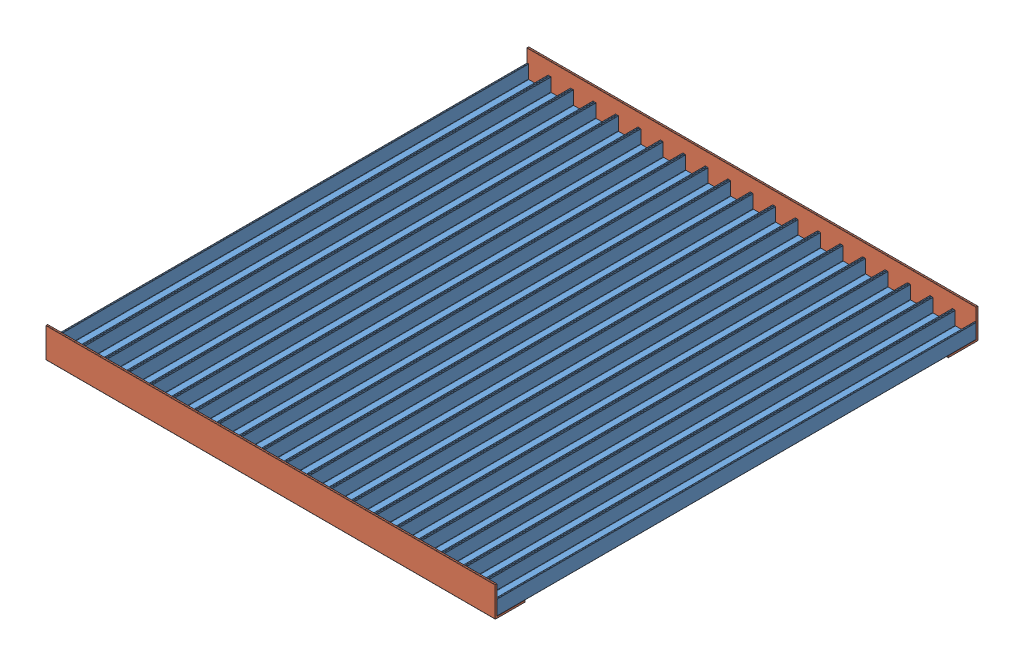
SolidWorks assembly Сборка1, configuration По умолчанию. Lengths in mm.
Overall size (300 20 322.4).
22 component instances, 2 part files, 97 mates.
Components (placement in the parent):
- hot_bed_profile-1: hot_bed_profile [По умолчанию] at (155.3452 184.886 41.526) size (15 10 320)
- hot_bed_profile-2: hot_bed_profile [По умолчанию] at (140.3452 184.886 41.526) size (15 10 320)
- hot_bed_profile-3: hot_bed_profile [По умолчанию] at (185.3452 184.886 41.526) size (15 10 320)
- hot_bed_profile-4: hot_bed_profile [По умолчанию] at (170.3452 184.886 41.526) size (15 10 320)
- hot_bed_profile-7: hot_bed_profile [По умолчанию] at (230.3452 184.886 41.526) size (15 10 320)
- hot_bed_profile-8: hot_bed_profile [По умолчанию] at (215.3452 184.886 41.526) size (15 10 320)
- hot_bed_profile-9: hot_bed_profile [По умолчанию] at (200.3452 184.886 41.526) size (15 10 320)
- hot_bed_profile-10: hot_bed_profile [По умолчанию] at (245.3452 184.886 41.526) size (15 10 320)
- hot_bed_profile-11: hot_bed_profile [По умолчанию] at (365.3452 184.886 41.526) size (15 10 320)
- hot_bed_profile-12: hot_bed_profile [По умолчанию] at (320.3452 184.886 41.526) size (15 10 320)
- hot_bed_profile-13: hot_bed_profile [По умолчанию] at (335.3452 184.886 41.526) size (15 10 320)
- hot_bed_profile-14: hot_bed_profile [По умолчанию] at (350.3452 184.886 41.526) size (15 10 320)
- hot_bed_profile-15: hot_bed_profile [По умолчанию] at (290.3452 184.886 41.526) size (15 10 320)
- hot_bed_profile-16: hot_bed_profile [По умолчанию] at (275.3452 184.886 41.526) size (15 10 320)
- hot_bed_profile-17: hot_bed_profile [По умолчанию] at (260.3452 184.886 41.526) size (15 10 320)
- hot_bed_profile-18: hot_bed_profile [По умолчанию] at (305.3452 184.886 41.526) size (15 10 320)
- hot_bed_profile-19: hot_bed_profile [По умолчанию] at (395.3452 184.886 41.526) size (15 10 320)
- hot_bed_profile-20: hot_bed_profile [По умолчанию] at (380.3452 184.886 41.526) size (15 10 320)
- hot_bed_profile-26: hot_bed_profile [По умолчанию] at (410.3452 184.886 41.526) size (15 10 320)
- hot_bed_profile-27: hot_bed_profile [По умолчанию] at (425.3452 184.886 41.526) size (15 10 320)
- hot_bed_profile_corner-1: hot_bed_profile_corner [По умолчанию] at (440.3452 194.6038 362.726) x (0 1 0) z (0 0 1) size (20 300 20)
- hot_bed_profile_corner-3: hot_bed_profile_corner [По умолчанию] at (440.3452 183.686 51.2438) x (0 0 1) z (0 -1 0) size (20 300 20)
Mates (geometry in assembly coordinates):
- Совпадение2: coincident anti-aligned: line of hot_bed_profile-1 through (155.3452 185.086 361.526) axis (0 1 0); line of hot_bed_profile-2 through (155.3452 194.686 361.526) axis (0 -1 0)
- Совпадение3: coincident anti-aligned: plane of hot_bed_profile-1 through (155.3452 185.086 361.526) normal (-1 0 0); plane of hot_bed_profile-2 through (155.3452 194.686 361.526) normal (1 0 0)
- Совпадение4: coincident anti-aligned: plane of hot_bed_profile-3 through (185.3452 185.086 361.526) normal (-1 0 0); plane of hot_bed_profile-4 through (185.3452 194.686 361.526) normal (1 0 0)
- Совпадение5: coincident anti-aligned: line of hot_bed_profile-3 through (185.3452 185.086 361.526) axis (0 1 0); line of hot_bed_profile-4 through (185.3452 194.686 361.526) axis (0 -1 0)
- Совпадение7: coincident aligned: plane of hot_bed_profile-1 through (156.1452 194.686 361.526) normal (0 0 1); plane of hot_bed_profile-4 through (171.1452 194.686 361.526) normal (0 0 1)
- Совпадение10: coincident aligned: plane of hot_bed_profile-3 through (186.1452 194.686 361.526) normal (0 0 1); plane of hot_bed_profile-4 through (171.1452 194.686 361.526) normal (0 0 1)
- Совпадение13: coincident anti-aligned: plane of hot_bed_profile-1 through (170.3452 194.686 361.526) normal (1 0 0); plane of hot_bed_profile-4 through (170.3452 185.086 361.526) normal (-1 0 0)
- Совпадение14: coincident anti-aligned: plane of hot_bed_profile-1 through (170.3452 194.686 361.526) normal (1 0 0); plane of hot_bed_profile-4 through (170.3452 185.086 361.526) normal (-1 0 0)
- Совпадение15: coincident anti-aligned: plane of hot_bed_profile-1 through (155.3452 185.086 361.526) normal (-1 0 0); plane of hot_bed_profile-2 through (155.3452 194.686 361.526) normal (1 0 0)
- Совпадение18: coincident anti-aligned: plane of hot_bed_profile-8 through (215.3452 185.086 361.526) normal (-1 0 0); plane of hot_bed_profile-9 through (215.3452 194.686 361.526) normal (1 0 0)
- Совпадение19: coincident aligned: plane of hot_bed_profile-7 through (231.1452 194.686 361.526) normal (0 0 1); plane of hot_bed_profile-10 through (246.1452 194.686 361.526) normal (0 0 1)
- Совпадение20: coincident anti-aligned: line of hot_bed_profile-7 through (245.3452 194.686 361.526) axis (0 -1 0); line of hot_bed_profile-10 through (245.3452 185.086 361.526) axis (0 1 0)
- Совпадение21: coincident anti-aligned: plane of hot_bed_profile-8 through (215.3452 185.086 361.526) normal (-1 0 0); plane of hot_bed_profile-9 through (215.3452 194.686 361.526) normal (1 0 0)
- Совпадение22: coincident anti-aligned: plane of hot_bed_profile-7 through (245.3452 194.686 361.526) normal (1 0 0); plane of hot_bed_profile-10 through (245.3452 185.086 361.526) normal (-1 0 0)
- Совпадение23: coincident anti-aligned: plane of hot_bed_profile-7 through (230.3452 185.086 361.526) normal (-1 0 0); plane of hot_bed_profile-8 through (230.3452 194.686 361.526) normal (1 0 0)
- Совпадение24: coincident aligned: plane of hot_bed_profile-7 through (231.1452 194.686 361.526) normal (0 0 1); plane of hot_bed_profile-8 through (216.1452 194.686 361.526) normal (0 0 1)
- Совпадение25: coincident anti-aligned: line of hot_bed_profile-8 through (215.3452 185.086 361.526) axis (0 1 0); line of hot_bed_profile-9 through (215.3452 194.686 361.526) axis (0 -1 0)
- Совпадение26: coincident anti-aligned: plane of hot_bed_profile-7 through (230.3452 185.086 361.526) normal (-1 0 0); plane of hot_bed_profile-8 through (230.3452 194.686 361.526) normal (1 0 0)
- Совпадение28: coincident anti-aligned: plane of hot_bed_profile-3 through (200.3452 194.686 361.526) normal (1 0 0); plane of hot_bed_profile-9 through (200.3452 185.086 361.526) normal (-1 0 0)
- Совпадение29: coincident anti-aligned: plane of hot_bed_profile-3 through (200.3452 194.686 361.526) normal (1 0 0); plane of hot_bed_profile-9 through (200.3452 185.086 361.526) normal (-1 0 0)
- Совпадение31: coincident anti-aligned: plane of hot_bed_profile-3 through (200.3452 194.686 361.526) normal (1 0 0); plane of hot_bed_profile-9 through (200.3452 185.086 361.526) normal (-1 0 0)
- Совпадение32: coincident anti-aligned: plane of hot_bed_profile-12 through (320.3452 185.086 361.526) normal (-1 0 0); plane of hot_bed_profile-18 through (320.3452 194.686 361.526) normal (1 0 0)
- Совпадение33: coincident anti-aligned: plane of hot_bed_profile-16 through (275.3452 185.086 361.526) normal (-1 0 0); plane of hot_bed_profile-17 through (275.3452 194.686 361.526) normal (1 0 0)
- Совпадение34: coincident anti-aligned: plane of hot_bed_profile-11 through (365.3452 185.086 361.526) normal (-1 0 0); plane of hot_bed_profile-14 through (365.3452 194.686 361.526) normal (1 0 0)
- Совпадение35: coincident anti-aligned: plane of hot_bed_profile-12 through (335.3452 194.686 361.526) normal (1 0 0); plane of hot_bed_profile-13 through (335.3452 185.086 361.526) normal (-1 0 0)
- Совпадение36: coincident aligned: plane of hot_bed_profile-13 through (336.1452 194.686 361.526) normal (0 0 1); plane of hot_bed_profile-14 through (351.1452 194.686 361.526) normal (0 0 1)
- Совпадение37: coincident anti-aligned: plane of hot_bed_profile-13 through (350.3452 194.686 361.526) normal (1 0 0); plane of hot_bed_profile-14 through (350.3452 185.086 361.526) normal (-1 0 0)
- Совпадение38: coincident aligned: plane of hot_bed_profile-11 through (366.1452 194.686 361.526) normal (0 0 1); plane of hot_bed_profile-14 through (351.1452 194.686 361.526) normal (0 0 1)
- Совпадение39: coincident anti-aligned: line of hot_bed_profile-11 through (365.3452 185.086 361.526) axis (0 1 0); line of hot_bed_profile-14 through (365.3452 194.686 361.526) axis (0 -1 0)
- Совпадение40: coincident anti-aligned: line of hot_bed_profile-12 through (335.3452 194.686 361.526) axis (0 -1 0); line of hot_bed_profile-13 through (335.3452 185.086 361.526) axis (0 1 0)
- Совпадение41: coincident anti-aligned: plane of hot_bed_profile-13 through (350.3452 194.686 361.526) normal (1 0 0); plane of hot_bed_profile-14 through (350.3452 185.086 361.526) normal (-1 0 0)
- Совпадение42: coincident anti-aligned: plane of hot_bed_profile-12 through (335.3452 194.686 361.526) normal (1 0 0); plane of hot_bed_profile-13 through (335.3452 185.086 361.526) normal (-1 0 0)
- Совпадение43: coincident aligned: plane of hot_bed_profile-15 through (291.1452 194.686 361.526) normal (0 0 1); plane of hot_bed_profile-18 through (306.1452 194.686 361.526) normal (0 0 1)
- Совпадение44: coincident anti-aligned: line of hot_bed_profile-15 through (305.3452 194.686 361.526) axis (0 -1 0); line of hot_bed_profile-18 through (305.3452 185.086 361.526) axis (0 1 0)
- Совпадение45: coincident anti-aligned: plane of hot_bed_profile-16 through (275.3452 185.086 361.526) normal (-1 0 0); plane of hot_bed_profile-17 through (275.3452 194.686 361.526) normal (1 0 0)
- Совпадение46: coincident anti-aligned: plane of hot_bed_profile-15 through (305.3452 194.686 361.526) normal (1 0 0); plane of hot_bed_profile-18 through (305.3452 185.086 361.526) normal (-1 0 0)
- Совпадение47: coincident anti-aligned: plane of hot_bed_profile-15 through (290.3452 185.086 361.526) normal (-1 0 0); plane of hot_bed_profile-16 through (290.3452 194.686 361.526) normal (1 0 0)
- Совпадение48: coincident anti-aligned: plane of hot_bed_profile-12 through (320.3452 185.086 361.526) normal (-1 0 0); plane of hot_bed_profile-18 through (320.3452 194.686 361.526) normal (1 0 0)
- Совпадение49: coincident aligned: plane of hot_bed_profile-15 through (291.1452 194.686 361.526) normal (0 0 1); plane of hot_bed_profile-16 through (276.1452 194.686 361.526) normal (0 0 1)
- Совпадение50: coincident anti-aligned: line of hot_bed_profile-16 through (275.3452 185.086 361.526) axis (0 1 0); line of hot_bed_profile-17 through (275.3452 194.686 361.526) axis (0 -1 0)
- Совпадение51: coincident anti-aligned: plane of hot_bed_profile-12 through (320.3452 185.086 361.526) normal (-1 0 0); plane of hot_bed_profile-18 through (320.3452 194.686 361.526) normal (1 0 0)
- Совпадение52: coincident anti-aligned: plane of hot_bed_profile-15 through (290.3452 185.086 361.526) normal (-1 0 0); plane of hot_bed_profile-16 through (290.3452 194.686 361.526) normal (1 0 0)
- Совпадение53: coincident anti-aligned: line of hot_bed_profile-19 through (395.3452 185.086 361.526) axis (0 1 0); line of hot_bed_profile-20 through (395.3452 194.686 361.526) axis (0 -1 0)
- Совпадение54: coincident aligned: plane of hot_bed_profile-19 through (396.1452 194.686 361.526) normal (0 0 1); plane of hot_bed_profile-20 through (381.1452 194.686 361.526) normal (0 0 1)
- Совпадение55: coincident anti-aligned: plane of hot_bed_profile-19 through (395.3452 185.086 361.526) normal (-1 0 0); plane of hot_bed_profile-20 through (395.3452 194.686 361.526) normal (1 0 0)
- Совпадение56: coincident anti-aligned: plane of hot_bed_profile-10 through (260.3452 194.686 361.526) normal (1 0 0); plane of hot_bed_profile-17 through (260.3452 185.086 361.526) normal (-1 0 0)
- Совпадение57: coincident anti-aligned: plane of hot_bed_profile-11 through (380.3452 194.686 361.526) normal (1 0 0); plane of hot_bed_profile-20 through (380.3452 185.086 361.526) normal (-1 0 0)
- Совпадение58: coincident aligned: plane of hot_bed_profile-4 through (185.1452 184.886 361.526) normal (0 -1 0); plane of hot_bed_profile-2 through (155.1452 184.886 361.526) normal (0 -1 0)
- Совпадение59: coincident aligned: plane of hot_bed_profile-4 through (185.1452 184.886 361.526) normal (0 -1 0); plane of hot_bed_profile-1 through (170.1452 184.886 361.526) normal (0 -1 0)
- Совпадение60: coincident aligned: plane of hot_bed_profile-4 through (185.1452 184.886 361.526) normal (0 -1 0); plane of hot_bed_profile-3 through (200.1452 184.886 361.526) normal (0 -1 0)
- Совпадение61: coincident aligned: plane of hot_bed_profile-4 through (185.1452 184.886 361.526) normal (0 -1 0); plane of hot_bed_profile-9 through (215.1452 184.886 361.526) normal (0 -1 0)
- Совпадение62: coincident aligned: plane of hot_bed_profile-4 through (185.1452 184.886 361.526) normal (0 -1 0); plane of hot_bed_profile-8 through (230.1452 184.886 361.526) normal (0 -1 0)
- Совпадение63: coincident aligned: plane of hot_bed_profile-4 through (185.1452 184.886 361.526) normal (0 -1 0); plane of hot_bed_profile-7 through (245.1452 184.886 361.526) normal (0 -1 0)
- Совпадение64: coincident aligned: plane of hot_bed_profile-4 through (185.1452 184.886 361.526) normal (0 -1 0); plane of hot_bed_profile-10 through (260.1452 184.886 361.526) normal (0 -1 0)
- Совпадение65: coincident aligned: plane of hot_bed_profile-4 through (185.1452 184.886 361.526) normal (0 -1 0); plane of hot_bed_profile-17 through (275.1452 184.886 361.526) normal (0 -1 0)
- Совпадение66: coincident aligned: plane of hot_bed_profile-4 through (185.1452 184.886 361.526) normal (0 -1 0); plane of hot_bed_profile-16 through (290.1452 184.886 361.526) normal (0 -1 0)
- Совпадение67: coincident aligned: plane of hot_bed_profile-4 through (185.1452 184.886 361.526) normal (0 -1 0); plane of hot_bed_profile-15 through (305.1452 184.886 361.526) normal (0 -1 0)
- Совпадение68: coincident aligned: plane of hot_bed_profile-4 through (185.1452 184.886 361.526) normal (0 -1 0); plane of hot_bed_profile-18 through (320.1452 184.886 361.526) normal (0 -1 0)
- Совпадение69: coincident aligned: plane of hot_bed_profile-4 through (185.1452 184.886 361.526) normal (0 -1 0); plane of hot_bed_profile-12 through (335.1452 184.886 361.526) normal (0 -1 0)
- Совпадение70: coincident aligned: plane of hot_bed_profile-4 through (185.1452 184.886 361.526) normal (0 -1 0); plane of hot_bed_profile-13 through (350.1452 184.886 361.526) normal (0 -1 0)
- Совпадение71: coincident aligned: plane of hot_bed_profile-4 through (185.1452 184.886 361.526) normal (0 -1 0); plane of hot_bed_profile-14 through (365.1452 184.886 361.526) normal (0 -1 0)
- Совпадение72: coincident aligned: plane of hot_bed_profile-4 through (185.1452 184.886 361.526) normal (0 -1 0); plane of hot_bed_profile-11 through (380.1452 184.886 361.526) normal (0 -1 0)
- Совпадение73: coincident aligned: plane of hot_bed_profile-4 through (185.1452 184.886 361.526) normal (0 -1 0); plane of hot_bed_profile-20 through (395.1452 184.886 361.526) normal (0 -1 0)
- Совпадение74: coincident aligned: plane of hot_bed_profile-4 through (185.1452 184.886 361.526) normal (0 -1 0); plane of hot_bed_profile-19 through (410.1452 184.886 361.526) normal (0 -1 0)
- Совпадение80: coincident anti-aligned: plane of hot_bed_profile-26 through (425.3452 194.686 361.526) normal (1 0 0); plane of hot_bed_profile-27 through (425.3452 185.086 361.526) normal (-1 0 0)
- Совпадение81: coincident aligned: plane of hot_bed_profile-26 through (411.1452 194.686 361.526) normal (0 0 1); plane of hot_bed_profile-27 through (426.1452 194.686 361.526) normal (0 0 1)
- Совпадение82: coincident anti-aligned: line of hot_bed_profile-26 through (425.3452 194.686 361.526) axis (0 -1 0); line of hot_bed_profile-27 through (425.3452 185.086 361.526) axis (0 1 0)
- Совпадение83: coincident anti-aligned: plane of hot_bed_profile-19 through (410.3452 194.686 361.526) normal (1 0 0); plane of hot_bed_profile-26 through (410.3452 185.086 361.526) normal (-1 0 0)
- Совпадение84: coincident anti-aligned: plane of hot_bed_profile-26 through (425.3452 194.686 361.526) normal (1 0 0); plane of hot_bed_profile-27 through (425.3452 185.086 361.526) normal (-1 0 0)
- Совпадение85: coincident aligned: plane of hot_bed_profile-19 through (410.1452 184.886 361.526) normal (0 -1 0); plane of hot_bed_profile-26 through (425.1452 184.886 361.526) normal (0 -1 0)
- Совпадение86: coincident aligned: plane of hot_bed_profile-11 through (380.1452 184.886 361.526) normal (0 -1 0); plane of hot_bed_profile-20 through (395.1452 184.886 361.526) normal (0 -1 0)
- Совпадение87: coincident aligned: plane of hot_bed_profile-26 through (425.1452 184.886 361.526) normal (0 -1 0); plane of hot_bed_profile-27 through (440.1452 184.886 361.526) normal (0 -1 0)
- Совпадение88: coincident aligned: plane of hot_bed_profile-20 through (381.1452 194.686 361.526) normal (0 0 1); plane of hot_bed_profile-11 through (366.1452 194.686 361.526) normal (0 0 1)
- Совпадение89: coincident aligned: plane of hot_bed_profile-20 through (381.1452 194.686 361.526) normal (0 0 1); plane of hot_bed_profile-19 through (396.1452 194.686 361.526) normal (0 0 1)
- Совпадение90: coincident aligned: plane of hot_bed_profile-20 through (381.1452 194.686 361.526) normal (0 0 1); plane of hot_bed_profile-26 through (411.1452 194.686 361.526) normal (0 0 1)
- Совпадение91: coincident aligned: plane of hot_bed_profile-20 through (381.1452 194.686 361.526) normal (0 0 1); plane of hot_bed_profile-27 through (426.1452 194.686 361.526) normal (0 0 1)
- Совпадение92: coincident aligned: plane of hot_bed_profile-20 through (381.1452 194.686 361.526) normal (0 0 1); plane of hot_bed_profile-14 through (351.1452 194.686 361.526) normal (0 0 1)
- Совпадение94: coincident aligned: plane of hot_bed_profile-20 through (381.1452 194.686 361.526) normal (0 0 1); plane of hot_bed_profile-13 through (336.1452 194.686 361.526) normal (0 0 1)
- Совпадение95: coincident aligned: plane of hot_bed_profile-20 through (381.1452 194.686 361.526) normal (0 0 1); plane of hot_bed_profile-12 through (321.1452 194.686 361.526) normal (0 0 1)
- Совпадение96: coincident aligned: plane of hot_bed_profile-20 through (381.1452 194.686 361.526) normal (0 0 1); plane of hot_bed_profile-18 through (306.1452 194.686 361.526) normal (0 0 1)
- Совпадение97: coincident aligned: plane of hot_bed_profile-20 through (381.1452 194.686 361.526) normal (0 0 1); plane of hot_bed_profile-15 through (291.1452 194.686 361.526) normal (0 0 1)
- Совпадение98: coincident aligned: plane of hot_bed_profile-20 through (381.1452 194.686 361.526) normal (0 0 1); plane of hot_bed_profile-16 through (276.1452 194.686 361.526) normal (0 0 1)
- Совпадение99: coincident aligned: plane of hot_bed_profile-20 through (381.1452 194.686 361.526) normal (0 0 1); plane of hot_bed_profile-17 through (261.1452 194.686 361.526) normal (0 0 1)
- Совпадение100: coincident aligned: plane of hot_bed_profile-20 through (381.1452 194.686 361.526) normal (0 0 1); plane of hot_bed_profile-10 through (246.1452 194.686 361.526) normal (0 0 1)
- Совпадение101: coincident aligned: plane of hot_bed_profile-20 through (381.1452 194.686 361.526) normal (0 0 1); plane of hot_bed_profile-7 through (231.1452 194.686 361.526) normal (0 0 1)
- Совпадение102: coincident aligned: plane of hot_bed_profile-20 through (381.1452 194.686 361.526) normal (0 0 1); plane of hot_bed_profile-8 through (216.1452 194.686 361.526) normal (0 0 1)
- Совпадение103: coincident aligned: plane of hot_bed_profile-20 through (381.1452 194.686 361.526) normal (0 0 1); plane of hot_bed_profile-9 through (201.1452 194.686 361.526) normal (0 0 1)
- Совпадение104: coincident aligned: plane of hot_bed_profile-20 through (381.1452 194.686 361.526) normal (0 0 1); plane of hot_bed_profile-3 through (186.1452 194.686 361.526) normal (0 0 1)
- Совпадение105: coincident aligned: plane of hot_bed_profile-20 through (381.1452 194.686 361.526) normal (0 0 1); plane of hot_bed_profile-4 through (171.1452 194.686 361.526) normal (0 0 1)
- Совпадение106: coincident aligned: plane of hot_bed_profile-20 through (381.1452 194.686 361.526) normal (0 0 1); plane of hot_bed_profile-1 through (156.1452 194.686 361.526) normal (0 0 1)
- Совпадение107: coincident aligned: plane of hot_bed_profile-20 through (381.1452 194.686 361.526) normal (0 0 1); plane of hot_bed_profile-2 through (141.1452 194.686 361.526) normal (0 0 1)
- Совпадение108: coincident anti-aligned: plane of hot_bed_profile-16 through (290.1452 184.886 361.526) normal (0 -1 0); plane of hot_bed_profile_corner-1 through (140.3452 184.886 342.926) normal (0 1 0)
- Совпадение109: coincident anti-aligned: plane of hot_bed_profile-16 through (276.1452 194.686 361.526) normal (0 0 1); plane of hot_bed_profile_corner-1 through (140.3452 185.086 361.526) normal (0 0 -1)
- Совпадение110: coincident aligned: plane of hot_bed_profile-27 through (440.3452 194.686 361.526) normal (1 0 0); plane of hot_bed_profile_corner-1 through (440.3452 203.486 362.526) normal (1 0 0)
- Совпадение113: coincident: plane of hot_bed_profile-12 through (335.1452 184.886 361.526) normal (0 -1 0); plane of hot_bed_profile_corner-3 through (181.6277 178.9091 107.4431) normal (0 1 0)
- Совпадение114: coincident: plane of hot_bed_profile-13 through (336.1452 194.686 41.526) normal (0 0 -1); plane of hot_bed_profile_corner-3 through (140.3452 203.486 41.526) normal (0 0 1)
- Совпадение115: coincident aligned: plane of hot_bed_profile-27 through (440.3452 194.686 361.526) normal (1 0 0); plane of hot_bed_profile_corner-3 through (440.3452 183.886 60.126) normal (1 0 0)
